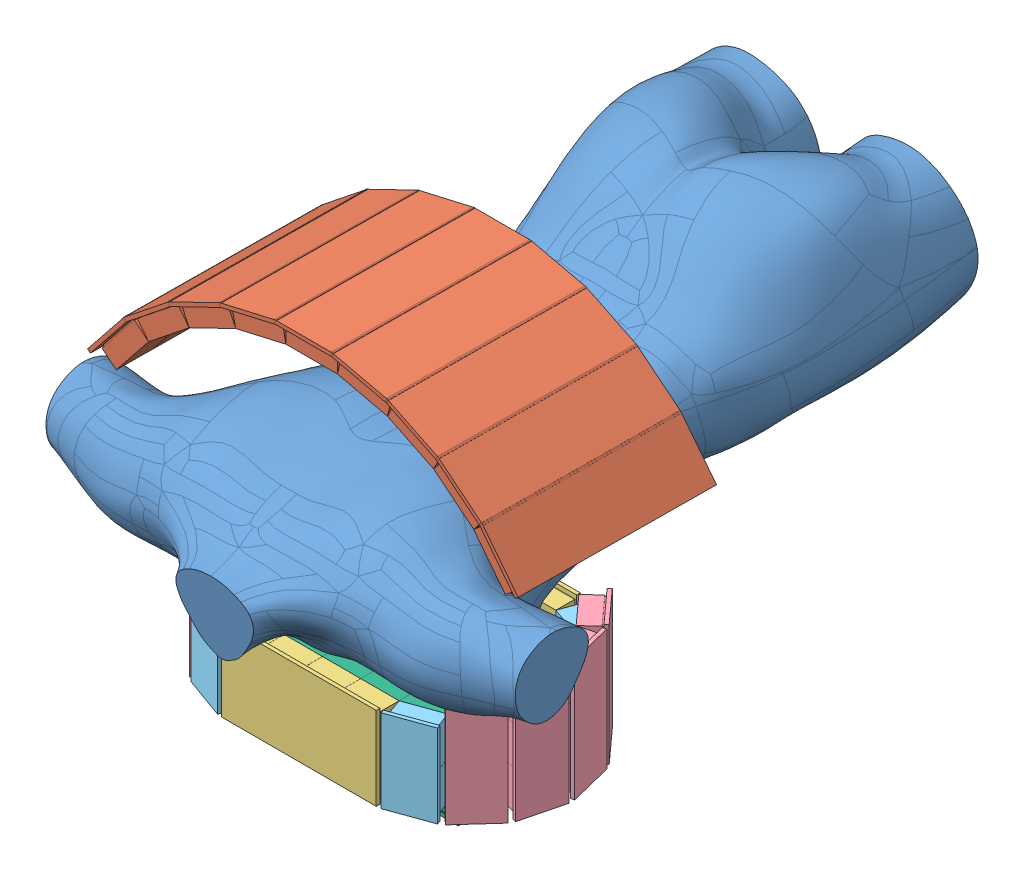
SolidWorks assembly Assem1, configuration Default. Lengths in mm.
Overall size (737.79 527.61 549.47).
36 component instances, 6 part files, 3 mates.
Components (placement in the parent):
- woman body-1: woman body [Default] at (196.8565 709.5111 506.493) x (1 0 0) z (0 -0.139173 0.990268) size (426.88 303.26 512.25)
- CshapedDetector1-2: CshapedDetector1 [Default] at (462.29 915.1834 874.4586) x (-0.900926 0.433957 -0.003787) z (0 0.008727 0.999962) size (527.59 312.86 270)
  - 5Detector-1: 5Detector [Default] at (91.8512 126.8436 184.2598) size (80 32 270)
  - 5Detector-2: 5Detector [Default] at (168.0955 135.4362 184.2598) x (0.974917 0.22257 0) z (0 0 1) size (80 32 270)
  - 5Detector-4: 5Detector [Default] at (240.515 160.783 184.2598) x (0.900926 0.433974 0) z (0 0 1) size (80 32 270)
  - 5Detector-5: 5Detector [Default] at (305.4764 201.6123 184.2598) x (0.781738 0.623607 0) z (0 0 1) size (80 32 270)
  - 5Detector-6: 5Detector [Default] at (359.7211 255.8759 184.2598) x (0.623334 0.781956 0) z (0 0 1) size (80 32 270)
  - 5Detector-7: 5Detector [Default] at (400.5278 320.8517 184.2598) x (0.433659 0.901077 0) z (0 0 1) size (80 32 270)
  - 5Detector-8: 5Detector [Default] at (15.6069 135.4362 184.2598) x (0.974917 -0.22257 0) z (0 0 1) size (80 32 270)
  - 5Detector-9: 5Detector [Default] at (-56.8125 160.783 184.2598) x (0.900926 -0.433974 0) z (0 0 1) size (80 32 270)
  - 5Detector-10: 5Detector [Default] at (425.8492 393.2799 184.2598) x (0.222229 0.974994 0) z (0 0 1) size (80 32 270)
- detectorassem-1: detectorassem [Default] at (165.9838 443.4414 957.2963) x (1 0 0) z (0 -1 0) size (517.67 317.54 193)
  - 52mmTOPBOTTOM-1: 52mmTOPBOTTOM [Default] at (-69.8528 -35.4842 8.7442) size (210.55 32 113)
  - SideDetector-1: SideDetector [Default] at (215.9367 233.9438 -54.2197) x (-0.242515 0.970148 0) z (0 0 1) size (268 155.36 165)
    - 52mmX4-1: 52mmX4 [Default] at (-99.1405 6.5957 36.9639) size (60 32 165)
    - 52mmX4-2: 52mmX4 [Default] at (-35.1412 22.594 36.9639) x (0.882373 0.47055 0) z (0 0 1) size (60 32 165)
    - 52mmX4-3: 52mmX4 [Default] at (-163.1399 22.594 36.9639) x (0.882373 -0.47055 0) z (0 0 1) size (60 32 165)
    - 52mmX4-4: 52mmX4 [Default] at (-212.0831 66.8254 36.9639) x (0.557166 -0.830401 0) z (0 0 1) size (60 32 165)
    - 52mmX3-1: 52mmX3 [Default] at (-234.4563 128.8843 62.9639) x (0.100883 -0.994898 0) z (0 0 1) size (60 32 113)
    - 52mmX3-2: 52mmX3 [Default] at (13.802 66.8254 62.9639) x (0.557166 0.830401 0) z (0 0 1) size (60 32 113)
  - SideDetector-2: SideDetector [Default] at (-199.3424 -27.5859 -54.2197) x (0.242515 -0.970148 0) z (0 0 1) size (268 155.36 165)
    - 52mmX4-1: 52mmX4 [Default] at (-99.1405 6.5957 36.9639) size (60 32 165)
    - 52mmX4-2: 52mmX4 [Default] at (-35.1412 22.594 36.9639) x (0.882373 0.47055 0) z (0 0 1) size (60 32 165)
    - 52mmX4-3: 52mmX4 [Default] at (-163.1399 22.594 36.9639) x (0.882373 -0.47055 0) z (0 0 1) size (60 32 165)
    - 52mmX4-4: 52mmX4 [Default] at (-212.0831 66.8254 36.9639) x (0.557166 -0.830401 0) z (0 0 1) size (60 32 165)
    - 52mmX3-1: 52mmX3 [Default] at (-234.4563 128.8843 62.9639) x (0.100883 -0.994898 0) z (0 0 1) size (60 32 113)
    - 52mmX3-2: 52mmX3 [Default] at (13.802 66.8254 62.9639) x (0.557166 0.830401 0) z (0 0 1) size (60 32 113)
  - 52mmTOPBOTTOM-2: 52mmTOPBOTTOM [Default] at (86.4472 241.8421 8.7442) x (-1 0 0) z (0 0 1) size (210.55 32 113)
  - 52mmAnterior-2: 52mmAnterior [Default] at (34.3328 154.0821 93.2442) x (1 0 0) z (0 1 0) size (312.06 32 157.26)
- SideDetector-1: SideDetector [Default] at (593.6345 497.6611 1191.1169) x (-0.258819 0 0.965926) z (0 -1 0) size (268 155.36 165) (hidden)
  - 52mmX4-1: 52mmX4 [Default] at (-99.1405 6.5957 36.9639) size (60 32 165)
  - 52mmX4-2: 52mmX4 [Default] at (-35.1412 22.594 36.9639) x (0.882373 0.47055 0) z (0 0 1) size (60 32 165)
  - 52mmX4-3: 52mmX4 [Default] at (-163.1399 22.594 36.9639) x (0.882373 -0.47055 0) z (0 0 1) size (60 32 165)
  - 52mmX4-4: 52mmX4 [Default] at (-212.0831 66.8254 36.9639) x (0.557166 -0.830401 0) z (0 0 1) size (60 32 165)
  - 52mmX3-1: 52mmX3 [Default] at (-234.4563 128.8843 62.9639) x (0.100883 -0.994898 0) z (0 0 1) size (60 32 113)
  - 52mmX3-2: 52mmX3 [Default] at (13.802 66.8254 62.9639) x (0.557166 0.830401 0) z (0 0 1) size (60 32 113)
Mates (geometry in assembly coordinates):
- Parallel4: parallel anti-aligned: line of detectorassem-1/52mmTOPBOTTOM-1 through (279.7759 378.1971 921.8121) axis (0 1 0); line of SideDetector-1/52mmX3-1 through (501.7769 491.1971 920.6435) axis (0 -1 0)
- Coincident9: coincident aligned: plane of detectorassem-1/52mmTOPBOTTOM-2 through (502.431 491.1971 1194.1383) normal (0 1 0); plane of SideDetector-1/52mmX3-2 through (552.2869 491.1971 1172.7237) normal (0 1 0)
- Parallel7: parallel anti-aligned: line of detectorassem-1/52mmTOPBOTTOM-2 through (279.3411 491.1971 1199.1383) axis (0 -1 0); line of SideDetector-1/52mmX3-2 through (497.1245 378.1971 1196.8506) axis (0 1 0)
